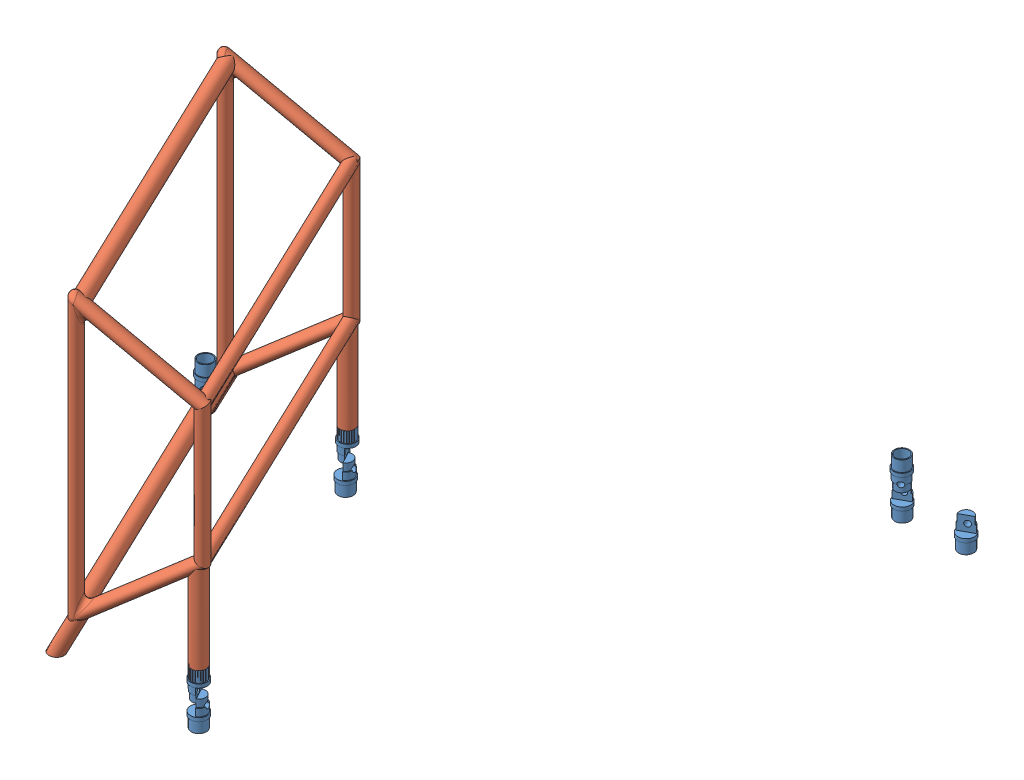
SolidWorks assembly Assem1, configuration Default. Lengths in mm.
Overall size (699.82 492.46 786.63).
9 component instances, 2 part files, 11 mates.
Components (placement in the parent):
- Plug-1: Plug [Default] at (18.1568 25.212 28.9639) size (23 40 23)
- Plug-2: Plug [Default] at (-654.299 60.212 399.8787) x (0.533456 0 -0.845828) z (-0.845828 0 -0.533456) size (23 40 23)
- Plug-3: Plug [Default] at (-0.207 123.5942 98.7713) x (0.533456 0 -0.845828) z (-0.845828 0 -0.533456) size (23 40 23)
- Plug-4: Plug [Default] at (0.1729 88.5942 98.5618) size (23 40 23)
- Plug-5: Plug [Default] at (-336.7383 -15.9406 726.4821) x (-0.016027 0 0.999872) z (-0.999872 0 -0.016027) size (23 40 23)
- Plug-6: Plug [Default] at (-336.6036 19.0594 726.7357) x (0.837169 0 0.546944) z (0.546944 0 -0.837169) size (23 40 23)
- Plug-7: Plug [Default] at (-519.5269 -18.8007 342.3231) x (-0.016027 0 0.999872) z (-0.999872 0 -0.016027) size (23 40 23)
- Plug-8: Plug [Default] at (-522.2704 16.1993 337.155) x (0.837169 0 0.546944) z (0.546944 0 -0.837169) size (23 40 23)
- Model1-1: Model1 [Default] at (-518.5561 256.9275 335.1862) x (0 1 0) z (0.430221 0 0.902724) size (433.23 169.23 453.24)
Mates (geometry in assembly coordinates):
- Coincident1: coincident anti-aligned: plane of Plug-1 through (18.1568 35.212 28.9639) normal (0.482982 0 0.87563); plane of Plug-2 through (-654.299 50.212 399.8787) normal (-0.482982 0 -0.87563)
- Distance1: distance = 15 mm anti-aligned: plane of Plug-2 through (-654.299 40.212 399.8787) normal (0 -1 0); plane of Plug-1 through (18.1568 25.212 28.9639) normal (0 1 0)
- Coincident8: coincident anti-aligned: plane of Plug-3 through (-0.207 113.5942 98.7713) normal (-0.482982 0 -0.87563); plane of Plug-4 through (0.1729 98.5942 98.5618) normal (0.482982 0 0.87563)
- Distance3: distance = 15 mm anti-aligned: plane of Plug-3 through (-0.207 103.5942 98.7713) normal (0 -1 0); plane of Plug-4 through (0.1729 88.5942 98.5618) normal (0 1 0)
- Coincident9: coincident anti-aligned: plane of Plug-5 through (-336.7383 -5.9406 726.4821) normal (-0.883259 0 0.468886); plane of Plug-6 through (-336.6036 9.0594 726.7357) normal (0.883259 0 -0.468886)
- Distance4: distance = 15 mm anti-aligned: plane of Plug-5 through (-336.7383 4.0594 726.4821) normal (0 1 0); plane of Plug-6 through (-336.6036 19.0594 726.7357) normal (0 -1 0)
- Coincident10: coincident anti-aligned: plane of Plug-7 through (-519.5269 -8.8007 342.3231) normal (-0.883259 0 0.468886); plane of Plug-8 through (-522.2704 6.1993 337.155) normal (0.883259 0 -0.468886)
- Distance5: distance = 15 mm anti-aligned: plane of Plug-7 through (-519.5269 1.1993 342.3231) normal (0 1 0); plane of Plug-8 through (-522.2704 16.1993 337.155) normal (0 -1 0)
- Concentric1: concentric anti-aligned: cylinder of Plug-2 through (-654.299 80.212 399.8787) axis (0 -1 0) radius 9; circle of Model1-1
- Concentric2: concentric anti-aligned: cylinder of Plug-8 through (-522.2704 36.1993 337.155) axis (0 -1 0) radius 9; cylinder of Model1-1 through (-522.2704 -8.6984 337.155) axis (0 1 0) radius 10.3
- Concentric3: concentric anti-aligned: cylinder of Plug-6 through (-336.6036 39.0594 726.7357) axis (0 -1 0) radius 9; cylinder of Model1-1 through (-336.6036 -8.6984 726.7357) axis (0 1 0) radius 10.3
